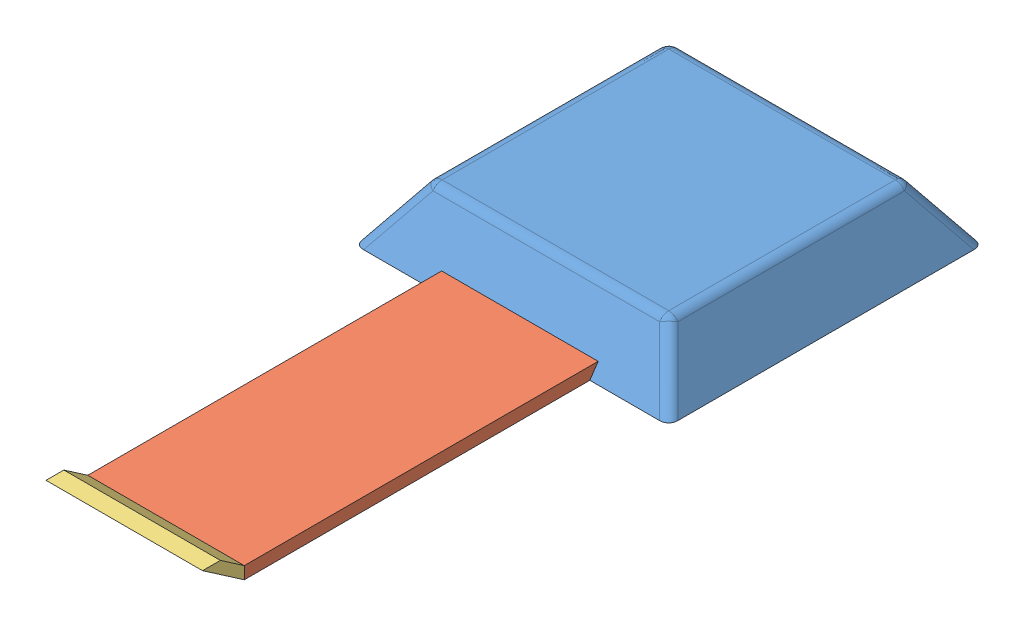
SolidWorks assembly oblivionhousehelipadassembly, configuration Default. Lengths in mm.
Overall size (2812 510 6276.33).
3 component instances, 3 part files, 6 mates.
Components (placement in the parent):
- oblivionhousehelipad-mpang-1: oblivionhousehelipad-mpang [Default] at (823.3479 1768.8833 2073.0787) size (2812 510 2812)
- oblivionhousehelipadpathway-mpang-1: oblivionhousehelipadpathway-mpang [Default] at (823.3479 1823.8833 6569.5787) x (-1 0 0) z (0 0 -1) size (1400 110 3483.5)
- oblivionhousehelipadslantedpathway-mpang-1: oblivionhousehelipadslantedpathway-mpang [Default] at (823.3479 1823.8833 6569.5787) x (-1 0 0) z (0 0 1) size (1400 257.64 373.83)
Mates (geometry in assembly coordinates):
- Coincident1: coincident anti-aligned: plane of oblivionhousehelipad-1 through (823.3479 1768.8833 3086.0787) normal (0 0 1); plane of oblivionhousehelipadpathway-mpang-1 through (823.3479 1823.8833 3086.0787) normal (0 0 -1)
- Coincident2: coincident anti-aligned: line of oblivionhousehelipad-1 through (1523.3479 1768.8833 3086.0787) axis (0 1 0); line of oblivionhousehelipadpathway-mpang-1 through (1523.3479 1878.8833 3086.0787) axis (0 -1 0)
- Coincident3: coincident anti-aligned: line of oblivionhousehelipad-1 through (1523.3479 1878.8833 3086.0787) axis (-1 0 0); line of oblivionhousehelipadpathway-mpang-1 through (123.3479 1878.8833 3086.0787) axis (1 0 0)
- Coincident4: coincident anti-aligned: line of oblivionhousehelipadpathway-mpang-1 through (1523.3479 1768.8833 6569.5787) axis (-1 0 0); line of oblivionhousehelipadslantedpathway-mpang-1 through (123.3479 1768.8833 6569.5787) axis (1 0 0)
- Coincident5: coincident anti-aligned: line of oblivionhousehelipadpathway-mpang-1 through (123.3479 1878.8833 6569.5787) axis (1 0 0); line of oblivionhousehelipadslantedpathway-mpang-1 through (1523.3479 1878.8833 6569.5787) axis (-1 0 0)
- Coincident6: coincident anti-aligned: line of oblivionhousehelipadpathway-mpang-1 through (123.3479 1768.8833 6569.5787) axis (0 1 0); line of oblivionhousehelipadslantedpathway-mpang-1 through (123.3479 1878.8833 6569.5787) axis (0 -1 0)
